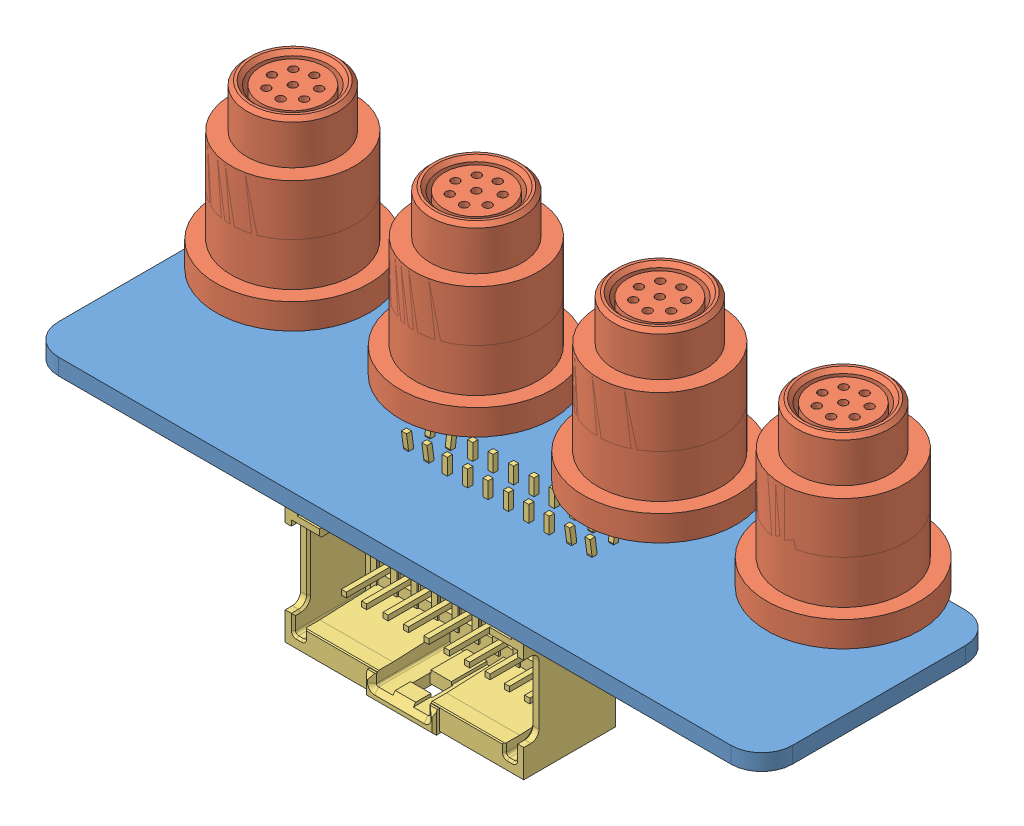
SolidWorks assembly Mid_MCN_Breakout, configuration Default. Lengths in mm.
Overall size (74.76 32.3 26.88).
6 component instances, 3 part files, 11 mates.
Components (placement in the parent):
- MMCNB_PCB-1: MMCNB_PCB [Default] at (-25.873 1.1687 4.8186) size (72 1.6 23)
- M8 Connector-1: M8 Connector [Default] at (-15.873 21.7687 -11.1814) x (-0.837169 0 -0.546944) z (-0.546944 0 0.837169) size (15 22 15)
- M8 Connector-2: M8 Connector [Default] at (2.127 21.7687 -11.1814) x (-0.837169 0 -0.546944) z (-0.546944 0 0.837169) size (15 22 15)
- M8 Connector-3: M8 Connector [Default] at (20.127 21.7687 -11.1814) x (-0.837169 0 -0.546944) z (-0.546944 0 0.837169) size (15 22 15)
- M8 Connector-4: M8 Connector [Default] at (38.127 21.7687 -11.1814) x (-0.837169 0 -0.546944) z (-0.546944 0 0.837169) size (15 22 15)
- MicroClasp_20_RA-1: MicroClasp_20_RA [Default] at (11.077 -3.8813 -2.1814) x (-1 0 0) z (0 1 0) size (23.4 14.5 14.9)
Mates (geometry in assembly coordinates):
- Coincident1: coincident anti-aligned: plane of MMCNB_PCB-1 through (-22.873 2.7687 1.8186) normal (0 1 0); plane of M8 Connector-1 through (-17.4823 2.7687 -10.2096) normal (0 -1 0)
- Concentric1: concentric: point of MMCNB_PCB-1; cylinder of M8 Connector-1 through (-15.873 8.2687 -11.1814) axis (0 1 0) radius 6.05
- Coincident3: coincident anti-aligned: plane of MMCNB_PCB-1 through (-22.873 2.7687 1.8186) normal (0 1 0); plane of M8 Connector-2 through (0.3638 2.7687 -11.8337) normal (0 -1 0)
- Concentric2: concentric: point of MMCNB_PCB-1; cylinder of M8 Connector-2 through (2.127 8.2687 -11.1814) axis (0 1 0) radius 6.05
- Coincident5: coincident anti-aligned: plane of MMCNB_PCB-1 through (-22.873 2.7687 1.8186) normal (0 1 0); plane of M8 Connector-3 through (21.4326 2.7687 -9.8287) normal (0 -1 0)
- Concentric3: concentric: point of MMCNB_PCB-1; cylinder of M8 Connector-3 through (20.127 8.2687 -11.1814) axis (0 1 0) radius 6.05
- Coincident7: coincident anti-aligned: plane of MMCNB_PCB-1 through (-22.873 2.7687 1.8186) normal (0 1 0); plane of M8 Connector-4 through (39.4326 2.7687 -9.8287) normal (0 -1 0)
- Concentric4: concentric: point of MMCNB_PCB-1; cylinder of M8 Connector-4 through (38.127 8.2687 -11.1814) axis (0 1 0) radius 6.05
- Coincident9: coincident anti-aligned: plane of MMCNB_PCB-1 through (-22.873 1.1687 1.8186) normal (0 -1 0); plane of MicroClasp_20_RA-1 through (22.777 1.1687 4.8186) normal (0 1 0)
- Coincident10: coincident aligned: plane of MMCNB_PCB-1 through (-22.873 2.7687 4.8186) normal (0 0 1); plane of MicroClasp_20_RA-1 through (22.777 -10.3313 4.8186) normal (0 0 1)
- Distance1: distance = 25.25 mm aligned: plane of MicroClasp_20_RA-1 through (-0.623 -3.8813 -2.1814) normal (-1 0 0); plane of MMCNB_PCB-1 through (-25.873 2.7687 1.8186) normal (-1 0 0)
